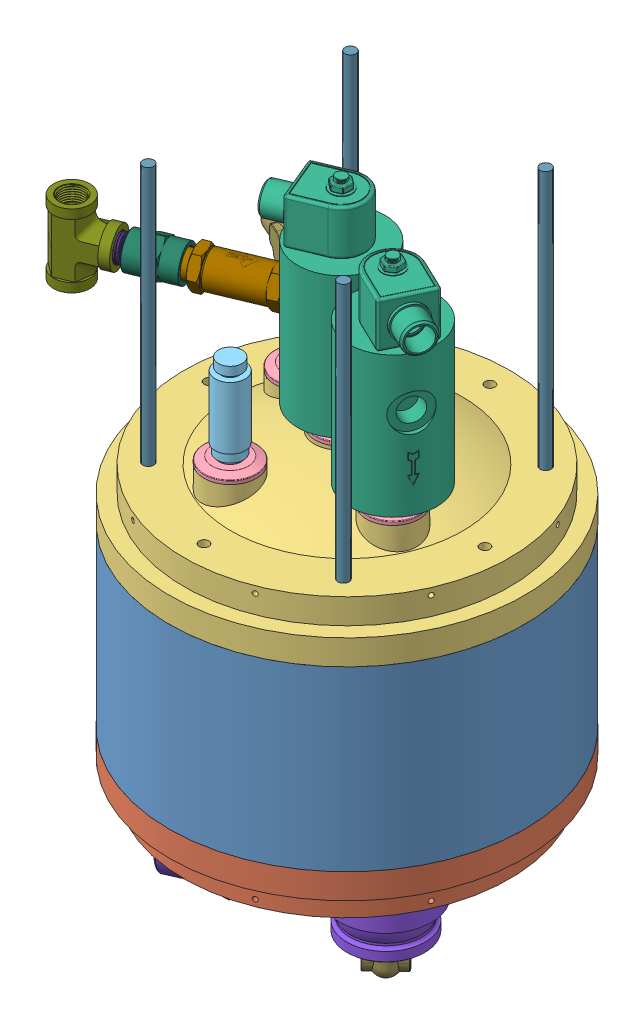
SolidWorks assembly 000053-R02_LOX_TANK_ASSM, configuration Default. Lengths in mm.
Overall size (401.08 613.31 401.08).
29 component instances, 17 part files, 50 mates.
Components (placement in the parent):
- 000055-R02_LOX_TANK_WALL-1: 000055-R02_LOX_TANK_WALL [Default] at origin size (304.8 152.4 304.8)
- 000052-R02b_TANK_BULKHEAD_BOTTOM-2: 000052-R02b_TANK_BULKHEAD_BOTTOM [Default] x (-0.398871 0 0.917007) z (0.917007 0 0.398871) size (304.8 66.04 304.8)
- 000052-R02a_TANK_BULKHEAD_TOP-1: 000052-R02a_TANK_BULKHEAD_TOP [Default] at (0 152.4 0) x (-0.917007 0 -0.398871) z (0.398871 0 -0.917007) size (304.8 66.04 304.8)
- FUELTANKPARTS-1-2-AL-FITTING-3: FUELTANKPARTS-1-2-AL-FITTING [Default] at (-69.8759 209.042 -30.394) x (0.997228 0 0.074408) z (-0.074408 0 0.997228) size (44.96 12.45 44.96)
- FUELTANKPARTS-1-2-AL-FITTING-4: FUELTANKPARTS-1-2-AL-FITTING [Default] at (-8.7345 211.582 -3.7993) x (0.985124 0 -0.171846) z (0.171846 0 0.985124) size (44.96 12.45 44.96)
- FUELTANKPARTS-1-2-AL-FITTING-9: FUELTANKPARTS-1-2-AL-FITTING [Default] at (-30.394 -56.642 69.8759) x (-0.381098 0 -0.924535) z (-0.924535 0 0.381098) size (44.96 12.45 44.96)
- FUELTANKPARTS-1-2-AL-FITTING-10: FUELTANKPARTS-1-2-AL-FITTING [Default] at (10.1313 -59.182 -23.292) x (-0.381098 0 -0.924535) z (-0.924535 0 0.381098) size (44.96 12.45 44.96)
- FUELTANKPARTS-1-2-AL-FITTING-12: FUELTANKPARTS-1-2-AL-FITTING [Default] at (-30.394 209.042 69.8759) x (0.074408 0 -0.997228) z (0.997228 0 0.074408) size (44.96 12.45 44.96)
- FUELTANKPARTS-1-2-AL-FITTING-13: FUELTANKPARTS-1-2-AL-FITTING [Default] at (69.8759 209.042 30.394) x (-0.997228 0 -0.074408) z (0.074408 0 -0.997228) size (44.96 12.45 44.96)
- cryo-pducer-temp-1: cryo-pducer-temp [Default] at (-30.394 211.328 69.8759) size (25.65 83.82 25.65)
- EH50-08-D024-OXXP-1: EH50-08-D024-OXXP [Default] at (-8.7345 311.3278 -3.7993) x (-0.922505 0 0.385985) z (-0.385985 0 -0.922505) size (87.5 168.84 74.93)
- CRVP4-500B-1: CRVP4-500B [Default] at (-69.8759 209.042 -30.394) x (0 1 0) z (0 0 1) size (82.27 25.15 25.15)
- atomatik-2: atomatik [Default] at (10.1313 -113.3517 -23.292) x (0 -1 0) z (-0.405568 0 -0.914065) size (76.23 180.98 78)
- TIN20021-1: TIN20021 [Default] at (-97.1889 311.3278 33.2109) x (0.922505 0 -0.385985) z (-0.385985 0 -0.922505) size (102.11 28.58 33)
- 44665K173_STANDARD-WALL ALUMINUM THREADED PIPE NIPPLE-1: 44665K173_STANDARD-WALL ALUMINUM THREADED PIPE NIPPLE [44665K173] at (69.8759 227.0379 30.394) x (-0.099238 0 -0.995064) z (0 1 0) size (22.19 22.36 51.97)
- 44665K173_STANDARD-WALL ALUMINUM THREADED PIPE NIPPLE-2: 44665K173_STANDARD-WALL ALUMINUM THREADED PIPE NIPPLE [44665K173] at (-8.7345 229.5779 -3.7993) x (0.19121 0 -0.981549) z (0 1 0) size (22.19 22.36 51.97)
- 44665K173_STANDARD-WALL ALUMINUM THREADED PIPE NIPPLE-3: 44665K173_STANDARD-WALL ALUMINUM THREADED PIPE NIPPLE [44665K173] at (10.1313 -77.1779 -23.292) x (-0.147711 0 -0.989031) z (0 1 0) size (22.19 22.36 51.97)
- 48805K184_PRECISION EXTREME-PRESSURE 316SS PIPE FITTING-1: 48805K184_PRECISION EXTREME-PRESSURE 316SS PIPE FITTING [48805K184] at (-30.394 -81.788 69.8759) x (0 -1 0) z (-0.983195 0 -0.182556) size (48.72 34.63 25.66)
- 3861T240_MED-PRESSURE ANODIZED ALUM THRD PIPE FITTING-2: 3861T240_MED-PRESSURE ANODIZED ALUM THRD PIPE FITTING [3861T24] at (-10.4238 -179.9821 -44.8205) x (-0.723269 0 0.690566) z (-0.690566 0 -0.723269) size (30.97 56.51 41.63)
- MCMASTER_94435A523_5in-5: MCMASTER_94435A523_5in [Default] at (-120.6313 -163.83 -2.1217) x (0 1 0) z (-0.995572 0 -0.094007) size (127 9.53 9.53)
- MCMASTER_94435A523_9in-5: MCMASTER_94435A523_9in [Default] at (-86.7995 189.23 83.799) x (0 1 0) z (-0.951783 0 0.306771) size (228.6 9.53 9.53)
- MCMASTER_94435A523_9in-6: MCMASTER_94435A523_9in [Default] at (83.799 189.23 86.7995) x (0 1 0) z (0.306771 0 0.951783) size (228.6 9.53 9.53)
- MCMASTER_94435A523_9in-7: MCMASTER_94435A523_9in [Default] at (86.7995 189.23 -83.799) x (0 1 0) z (0.951783 0 -0.306771) size (228.6 9.53 9.53)
- MCMASTER_94435A523_9in-8: MCMASTER_94435A523_9in [Default] at (-83.799 189.23 -86.7995) x (0 1 0) z (-0.306771 0 -0.951783) size (228.6 9.53 9.53)
- 3861T240_MED-PRESSURE ANODIZED ALUM THRD PIPE FITTING-3: 3861T240_MED-PRESSURE ANODIZED ALUM THRD PIPE FITTING [3861T24] at (-97.0429 312.3406 -42.5575) x (0.408641 0 -0.912695) z (-0.912695 0 -0.408641) size (30.97 56.51 41.63)
- 51205K223_EXTREME-PRESSURE 316 SS THREADED PIPE FITTING-1: 51205K223_EXTREME-PRESSURE 316 SS THREADED PIPE FITTING [51205K223] at (-119.4489 311.3278 42.5247) x (-0.385985 0 -0.922505) z (-0.922505 0 0.385985) size (28.7 32.74 38.1)
- 51205K245_EXTREME-PRESSURE 316 SS THREADED PIPE FITTING-1: 51205K245_EXTREME-PRESSURE 316 SS THREADED PIPE FITTING [51205K245] at (-171.8921 311.3278 64.4675) x (0 -1 0) z (0.385985 0 0.922505) size (63.86 47.51 31.16)
- 44665K211_STANDARD-WALL ALUMINUM THREADED PIPE NIPPLE-1: 44665K211_STANDARD-WALL ALUMINUM THREADED PIPE NIPPLE [44665K211] at (-142.1776 311.3278 52.0346) x (0.36865 0.296317 0.881075) z (-0.922505 0 0.385985) size (21.92 21.87 39.26)
- EH50-08-D024-OXXP-2: EH50-08-D024-OXXP [Default] at (69.8759 308.7878 30.394) x (0.900951 0 0.43392) z (-0.43392 0 0.900951) size (87.5 168.84 74.93)
Mates (geometry in assembly coordinates):
- Coincident1: coincident anti-aligned: axis of 000055-R02_LOX_TANK_WALL-1 through (152.4 0 152.4) axis (0 0 -1); axis of 000052-R02a_TANK_BULKHEAD_TOP-1 through (0 102.5587 0) axis (0 1 0)
- Coincident2: coincident aligned: axis of 000055-R02_LOX_TANK_WALL-1 through (152.4 0 152.4) axis (0 0 -1); axis of 000052-R02b_TANK_BULKHEAD_BOTTOM-2 through (0 0 0) axis (0 -1 0)
- Coincident3: coincident anti-aligned: plane of 000055-R02_LOX_TANK_WALL-1 through (0 152.4 0) normal (0 1 0); plane of 000052-R02a_TANK_BULKHEAD_TOP-1 through (-133.9289 152.4 -58.2552) normal (0 -1 0)
- Coincident4: coincident anti-aligned: plane of 000055-R02_LOX_TANK_WALL-1 through (0 0 0) normal (0 -1 0); plane of 000052-R02b_TANK_BULKHEAD_BOTTOM-2 through (-58.2552 0 133.9289) normal (0 1 0)
- Coincident7: coincident anti-aligned: plane of 000052-R02a_TANK_BULKHEAD_TOP-1 through (-8.7345 218.44 -3.7993) normal (0 1 0); plane of FUELTANKPARTS-1-2-AL-FITTING-4 through (-8.7345 218.44 -3.7993) normal (0 -1 0)
- Coincident9: coincident anti-aligned: plane of 000052-R02b_TANK_BULKHEAD_BOTTOM-2 through (-30.394 -63.5 69.8759) normal (0 -1 0); plane of FUELTANKPARTS-1-2-AL-FITTING-9 through (-30.394 -63.5 69.8759) normal (0 1 0)
- Concentric8: concentric anti-aligned: cylinder of 000052-R02b_TANK_BULKHEAD_BOTTOM-2 through (-30.394 -63.5 69.8759) axis (0 -1 0) radius 12.7; cylinder of FUELTANKPARTS-1-2-AL-FITTING-9 through (-30.394 -63.5 69.8759) axis (0 1 0) radius 12.7
- Coincident10: coincident anti-aligned: plane of 000052-R02b_TANK_BULKHEAD_BOTTOM-2 through (10.1313 -66.04 -23.292) normal (0 -1 0); plane of FUELTANKPARTS-1-2-AL-FITTING-10 through (10.1313 -66.04 -23.292) normal (0 1 0)
- Concentric9: concentric anti-aligned: cylinder of 000052-R02b_TANK_BULKHEAD_BOTTOM-2 through (10.1313 -66.04 -23.292) axis (0 -1 0) radius 12.7; cylinder of FUELTANKPARTS-1-2-AL-FITTING-10 through (10.1313 -66.04 -23.292) axis (0 1 0) radius 12.7
- Concentric10: concentric anti-aligned: cylinder of 000052-R02a_TANK_BULKHEAD_TOP-1 through (-69.8759 215.9 -30.394) axis (0 1 0) radius 12.7; cylinder of FUELTANKPARTS-1-2-AL-FITTING-3 through (-69.8759 215.9 -30.394) axis (0 -1 0) radius 12.7
- Coincident13: coincident anti-aligned: plane of 000052-R02a_TANK_BULKHEAD_TOP-1 through (-69.8759 215.9 -30.394) normal (0 1 0); plane of FUELTANKPARTS-1-2-AL-FITTING-3 through (-69.8759 215.9 -30.394) normal (0 -1 0)
- Concentric12: concentric anti-aligned: cylinder of FUELTANKPARTS-1-2-AL-FITTING-9 through (-30.394 -69.088 69.8759) axis (0 1 0) radius 9.271; cylinder of FUELTANKPARTS-1-2-AL-FITTING-12 through (-30.394 221.488 69.8759) axis (0 -1 0) radius 9.271
- Concentric13: concentric aligned: cylinder of FUELTANKPARTS-1-2-AL-FITTING-12 through (-30.394 221.488 69.8759) axis (0 -1 0) radius 9.271; cylinder of cryo-pducer-temp-1 through (-30.394 211.328 69.8759) axis (0 -1 0) radius 8.89
- Distance2: distance = 2.54 mm anti-aligned: plane of cryo-pducer-temp-1 through (-18.964 224.028 69.8759) normal (0 -1 0); plane of FUELTANKPARTS-1-2-AL-FITTING-12 through (-30.394 221.488 69.8759) normal (0 1 0)
- Concentric14: concentric anti-aligned: cylinder of FUELTANKPARTS-1-2-AL-FITTING-4 through (-8.7345 224.028 -3.7993) axis (0 -1 0) radius 9.271; cone of EH50-08-D024-OXXP-1 through (-8.7345 235.1278 -3.7993) axis (0 1 0)
- Concentric16: concentric anti-aligned: cylinder of 000052-R02a_TANK_BULKHEAD_TOP-1 through (-8.7345 218.44 -3.7993) axis (0 1 0) radius 12.7; cylinder of FUELTANKPARTS-1-2-AL-FITTING-4 through (-8.7345 218.44 -3.7993) axis (0 -1 0) radius 12.7
- Concentric19: concentric aligned: cylinder of FUELTANKPARTS-1-2-AL-FITTING-3 through (-69.8759 221.488 -30.394) axis (0 -1 0) radius 9.271; cone of CRVP4-500B-1 through (-69.8759 224.028 -30.394) axis (0 -1 0)
- Distance5: distance = 2.54 mm anti-aligned: plane of CRVP4-500B-1 through (-69.8759 224.028 -30.394) normal (0 -1 0); plane of FUELTANKPARTS-1-2-AL-FITTING-3 through (-69.8759 221.488 -30.394) normal (0 1 0)
- Concentric22: concentric aligned: cone of EH50-08-D024-OXXP-1 through (-40.0157 311.3278 9.2891) axis (0.922505 0 -0.385985); cone of TIN20021-1 through (-38.6977 311.3278 8.7376) axis (0.922505 0 -0.385985)
- Coincident26: coincident anti-aligned: plane of EH50-08-D024-OXXP-1 through (-40.0157 327.2028 9.2891) normal (-0.922505 0 0.385985); plane of TIN20021-1 through (-36.8318 311.3278 16.8988) normal (0.922505 0 -0.385985)
- Concentric32: concentric anti-aligned: cylinder of FUELTANKPARTS-1-2-AL-FITTING-13 through (69.8759 221.488 30.394) axis (0 -1 0) radius 9.271; cylinder of 44665K173_STANDARD-WALL ALUMINUM THREADED PIPE NIPPLE-1 through (69.8759 221.488 30.394) axis (0 1 0) radius 10.668
- Coincident35: coincident aligned: plane of FUELTANKPARTS-1-2-AL-FITTING-13 through (69.8759 221.488 30.394) normal (0 1 0); circle of 44665K173_STANDARD-WALL ALUMINUM THREADED PIPE NIPPLE-1
- Concentric34: concentric anti-aligned: cylinder of FUELTANKPARTS-1-2-AL-FITTING-4 through (-8.7345 224.028 -3.7993) axis (0 -1 0) radius 9.271; cylinder of 44665K173_STANDARD-WALL ALUMINUM THREADED PIPE NIPPLE-2 through (-8.7345 224.028 -3.7993) axis (0 1 0) radius 10.668
- Coincident37: coincident aligned: plane of EH50-08-D024-OXXP-1 through (-11.6634 235.1278 -2.5737) normal (0 -1 0); circle of 44665K173_STANDARD-WALL ALUMINUM THREADED PIPE NIPPLE-2
- Coincident38: coincident aligned: plane of FUELTANKPARTS-1-2-AL-FITTING-4 through (-8.7345 224.028 -3.7993) normal (0 1 0); circle of 44665K173_STANDARD-WALL ALUMINUM THREADED PIPE NIPPLE-2
- Concentric35: concentric aligned: cylinder of atomatik-2 through (10.1313 -137.9825 -23.292) axis (0 1 0) radius 16.775; cylinder of 44665K173_STANDARD-WALL ALUMINUM THREADED PIPE NIPPLE-3 through (10.1313 -82.7278 -23.292) axis (0 1 0) radius 10.668
- Concentric36: concentric aligned: cylinder of FUELTANKPARTS-1-2-AL-FITTING-10 through (10.1313 -71.628 -23.292) axis (0 1 0) radius 9.271; cylinder of 44665K173_STANDARD-WALL ALUMINUM THREADED PIPE NIPPLE-3 through (10.1313 -82.7278 -23.292) axis (0 1 0) radius 10.668
- Coincident39: coincident aligned: plane of FUELTANKPARTS-1-2-AL-FITTING-10 through (10.1313 -71.628 -23.292) normal (0 -1 0); circle of 44665K173_STANDARD-WALL ALUMINUM THREADED PIPE NIPPLE-3
- Coincident40: coincident aligned: plane of atomatik-2 through (25.4648 -82.7278 -30.0954) normal (0 1 0); circle of 44665K173_STANDARD-WALL ALUMINUM THREADED PIPE NIPPLE-3
- Concentric37: concentric aligned: cylinder of FUELTANKPARTS-1-2-AL-FITTING-9 through (-30.394 -69.088 69.8759) axis (0 1 0) radius 9.271; cylinder of 48805K184_PRECISION EXTREME-PRESSURE 316SS PIPE FITTING-1 through (-30.394 -81.788 69.8759) axis (0 1 0) radius 5.207
- Coincident41: coincident anti-aligned: plane of FUELTANKPARTS-1-2-AL-FITTING-9 through (-30.394 -69.088 69.8759) normal (0 -1 0); plane of 48805K184_PRECISION EXTREME-PRESSURE 316SS PIPE FITTING-1 through (-52.2455 -69.088 65.8186) normal (0 1 0)
- Concentric38: concentric aligned: cylinder of atomatik-2 through (10.1313 -137.9825 -23.292) axis (0 1 0) radius 16.775; cylinder of 3861T240_MED-PRESSURE ANODIZED ALUM THRD PIPE FITTING-2 through (10.1313 -162.1227 -23.292) axis (0 1 0) radius 6.7469
- Coincident42: coincident anti-aligned: plane of atomatik-2 through (31.2691 -158.9541 -32.6707) normal (0 -1 0); plane of 3861T240_MED-PRESSURE ANODIZED ALUM THRD PIPE FITTING-2 through (33.3722 -158.9541 -20.7894) normal (0 1 0)
- Concentric43: concentric aligned: cylinder of 000052-R02b_TANK_BULKHEAD_BOTTOM-2 through (-120.6313 -43.18 -2.1217) axis (0 -1 0) radius 4.2164; cylinder of MCMASTER_94435A523_5in-5 through (-120.6313 -36.83 -2.1217) axis (0 -1 0) radius 4.7625
- Distance7: distance = 6.35 mm anti-aligned: plane of MCMASTER_94435A523_5in-5 through (-120.6313 -36.83 -2.1217) normal (0 1 0); plane of 000052-R02b_TANK_BULKHEAD_BOTTOM-2 through (-55.7223 -43.18 128.1059) normal (0 -1 0)
- Concentric45: concentric anti-aligned: cylinder of 000052-R02a_TANK_BULKHEAD_TOP-1 through (-86.7995 195.58 83.799) axis (0 1 0) radius 4.2164; cylinder of MCMASTER_94435A523_9in-5 through (-86.7995 417.83 83.799) axis (0 -1 0) radius 4.7625
- Distance8: distance = 6.35 mm anti-aligned: plane of MCMASTER_94435A523_9in-5 through (-86.7995 189.23 83.799) normal (0 -1 0); plane of 000052-R02a_TANK_BULKHEAD_TOP-1 through (-128.1059 195.58 -55.7223) normal (0 1 0)
- Concentric46: concentric anti-aligned: cylinder of CRVP4-500B-1 through (-69.8759 262.382 -30.394) axis (0 1 0) radius 7.9375; cylinder of 3861T240_MED-PRESSURE ANODIZED ALUM THRD PIPE FITTING-3 through (-69.8759 294.4813 -30.394) axis (0 -1 0) radius 6.7469
- Coincident49: coincident anti-aligned: plane of CRVP4-500B-1 through (-69.8759 291.3126 -30.394) normal (0 1 0); plane of 3861T240_MED-PRESSURE ANODIZED ALUM THRD PIPE FITTING-3 through (-59.7386 291.3126 -9.3313) normal (0 -1 0)
- Concentric48: concentric aligned: cone of TIN20021-1 through (-98.5069 311.3278 33.7624) axis (-0.922505 0 0.385985); cylinder of 51205K223_EXTREME-PRESSURE 316 SS THREADED PIPE FITTING-1 through (-137.0227 311.3278 49.8778) axis (-0.922505 0 0.385985) radius 6.35
- Distance9: distance = 5.08 mm anti-aligned: plane of TIN20021-1 through (-94.0049 311.3278 40.8206) normal (-0.922505 0 0.385985); plane of 51205K223_EXTREME-PRESSURE 316 SS THREADED PIPE FITTING-1 through (-101.8752 311.3278 35.1717) normal (0.922505 0 -0.385985)
- Parallel2: parallel aligned: plane of 000052-R02a_TANK_BULKHEAD_TOP-1 through (-128.1059 195.58 -55.7223) normal (0 1 0); plane of TIN20021-1 through (-44.4677 325.6153 11.1519) normal (0 1 0)
- Angle2: planar angle = 0.523599 rad anti-aligned: plane of 51205K223_EXTREME-PRESSURE 316 SS THREADED PIPE FITTING-1 through (-74.0275 294.83 23.52) normal (0.192993 -0.866025 0.461253); plane of TIN20021-1 through (-93.2055 325.6153 31.5442) normal (0 1 0)
- Parallel3: parallel aligned: plane of 51205K223_EXTREME-PRESSURE 316 SS THREADED PIPE FITTING-1 through (-79.5423 319.5767 10.3397) normal (-0.385985 0 -0.922505); plane of 51205K245_EXTREME-PRESSURE 316 SS THREADED PIPE FITTING-1 through (-166.2926 299.6121 47.4973) normal (-0.385985 0 -0.922505)
- Concentric54: concentric anti-aligned: cylinder of 51205K223_EXTREME-PRESSURE 316 SS THREADED PIPE FITTING-1 through (-137.0227 311.3278 49.8778) axis (-0.922505 0 0.385985) radius 6.35; cylinder of 44665K211_STANDARD-WALL ALUMINUM THREADED PIPE NIPPLE-1 through (-160.293 311.3278 59.6143) axis (0.922505 0 -0.385985) radius 7.8994
- Concentric55: concentric anti-aligned: cylinder of 51205K245_EXTREME-PRESSURE 316 SS THREADED PIPE FITTING-1 through (-155.4899 311.3278 57.6046) axis (-0.922505 0 0.385985) radius 8.001; cylinder of 44665K211_STANDARD-WALL ALUMINUM THREADED PIPE NIPPLE-1 through (-160.293 311.3278 59.6143) axis (0.922505 0 -0.385985) radius 7.8994
- Coincident58: coincident anti-aligned: circle of 51205K223_EXTREME-PRESSURE 316 SS THREADED PIPE FITTING-1; plane of 44665K211_STANDARD-WALL ALUMINUM THREADED PIPE NIPPLE-1 through (-124.6039 311.3278 44.6816) normal (0.922505 0 -0.385985)
- Coincident59: coincident aligned: circle of 51205K245_EXTREME-PRESSURE 316 SS THREADED PIPE FITTING-1; plane of 44665K211_STANDARD-WALL ALUMINUM THREADED PIPE NIPPLE-1 through (-159.7513 311.3278 59.3877) normal (-0.922505 0 0.385985)
- Concentric56: concentric aligned: cylinder of 44665K173_STANDARD-WALL ALUMINUM THREADED PIPE NIPPLE-1 through (69.8759 221.488 30.394) axis (0 1 0) radius 10.668; cone of EH50-08-D024-OXXP-2 through (69.8759 232.5878 30.394) axis (0 1 0)
- Coincident60: coincident anti-aligned: circle of 44665K173_STANDARD-WALL ALUMINUM THREADED PIPE NIPPLE-1; plane of EH50-08-D024-OXXP-2 through (72.7364 232.5878 31.7717) normal (0 -1 0)
